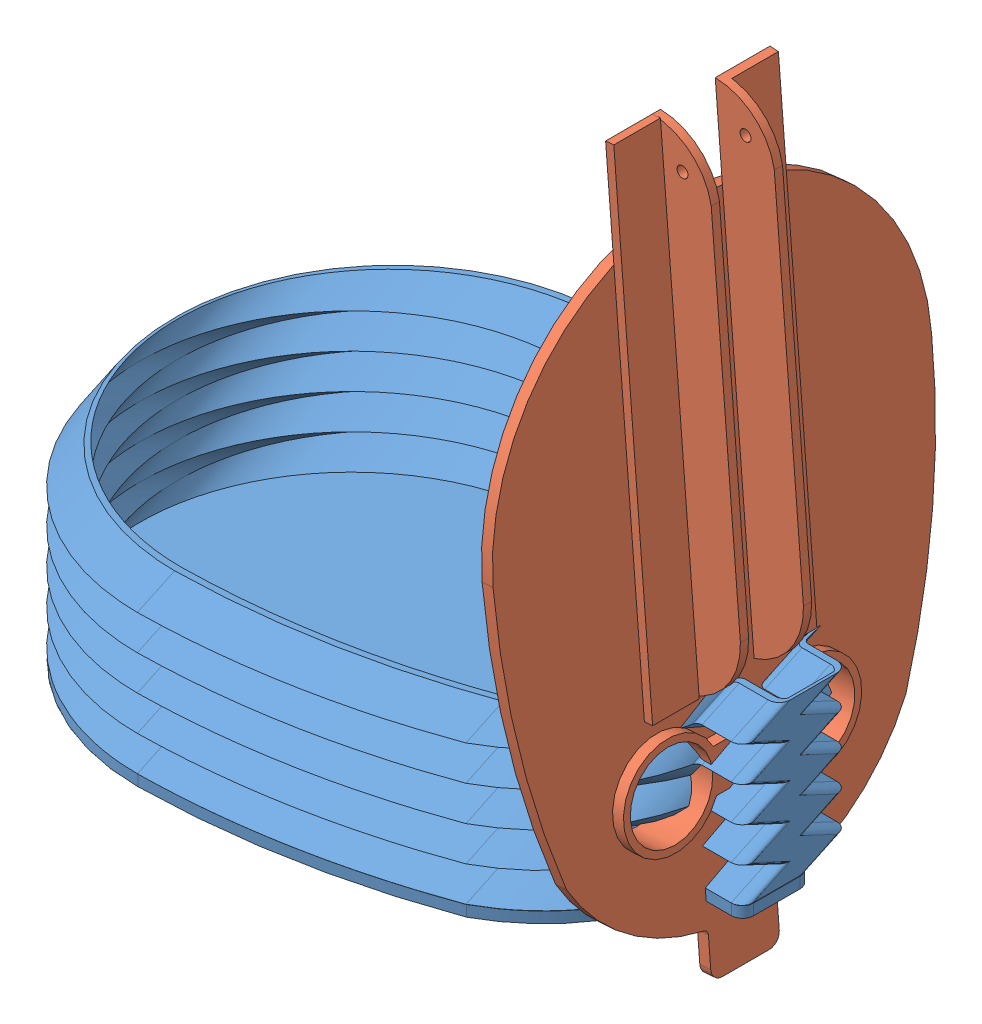
SolidWorks assembly Assem2, configuration Default. Lengths in mm.
Overall size (245.41 267.66 183.04).
2 component instances, 2 part files, 2 mates.
Components (placement in the parent):
- tapa de fuelle-1: tapa de fuelle [Default] at (-47.9983 -11.7162 7.7358) size (236.73 61.73 183.04)
- tapa sup de fuelle-1: tapa sup de fuelle [Default] at (51.7439 87.7349 7.7358) x (0.079967 -0.996797 0) z (0 0 1) size (265 43.89 160.08)
Mates (geometry in assembly coordinates):
- Concentric1: concentric: cylinder of tapa de fuelle-1 through (43.0291 -3.7162 62.7358) axis (0 0 -1) radius 2; cylinder of tapa sup de fuelle-1 through (43.0291 -3.7162 -26.2642) axis (0 0 1) radius 2
- Coincident1: coincident: plane of tapa de fuelle-1 through (40.0291 0.2838 32.7358) normal (0 0 -1); plane of tapa sup de fuelle-1 through (38.802 -1.0457 32.7358) normal (0 0 1)
